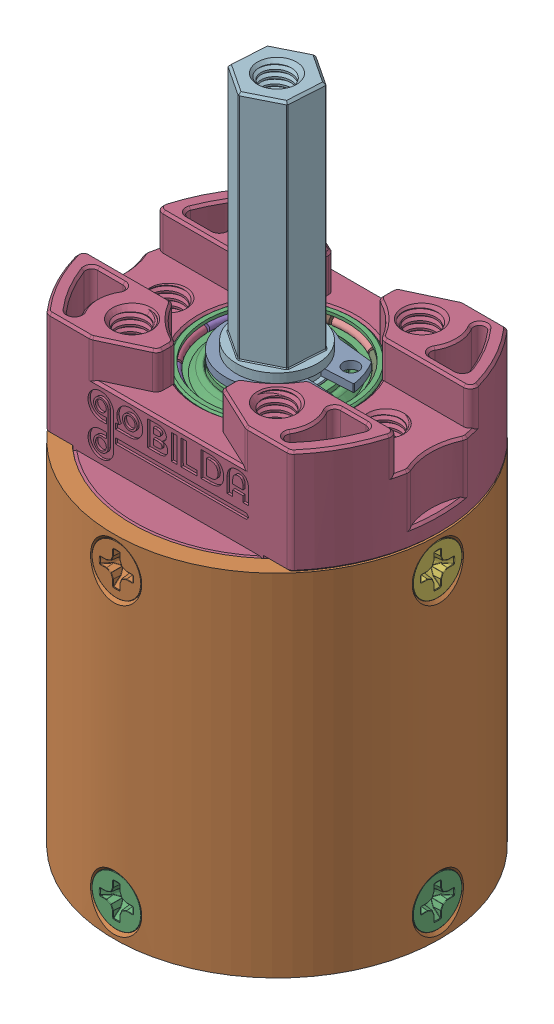
SolidWorks assembly Gearbox, configuration Default. Lengths in mm.
Overall size (36 76.68 35.96).
20 component instances, 8 part files, 0 mates.
Components (placement in the parent):
- Simple-1: Simple [Default] at (-74.1198 0.9931 -10.6145) size (36 73.8 35.96)
  - 5303 Gearbox Base-1: 5303 Gearbox Base [Default] at (-58.7206 21.0354 14.7927) size (31.9 5.6 31.9)
  - 5303 Gearbox Barrel (4 stage, simple)_Gear Blank-1: 5303 Gearbox Barrel (4 stage, simple)_Gear Blank [Default] at (-58.7206 99.2654 14.7927) x (1 0 0) z (0 -1 0) size (35.96 35.96 38.7)
  - 5303 Gearbox Barrel Screw (M3 x 8mm length Flat Head)_92010A118-1: 5303 Gearbox Barrel Screw (M3 x 8mm length Flat Head)_92010A118 [Default] at (-58.7206 24.5354 30.8757) x (0.002439 -0.999997 0) z (0 0 1) size (5.46 5.46 8.05)
  - 5303 Gearbox Face-1: 5303 Gearbox Face [Default] at (-58.7206 54.2354 14.7927) size (36 17.1 31.9)
  - 5303 Gearbox Bearing-1: 5303 Gearbox Bearing [Default] at (-58.7206 62.3354 14.7927) size (17 5 17)
  - 5303 Gearbox Shaft (23.5mm Length, Simple)-1: 5303 Gearbox Shaft (23.5mm Length, Simple) [Default] at (-58.7206 50.8754 14.7927) x (0.894773 0 -0.44652) z (0.44652 0 0.894773) size (8.97 40.6 8.97)
  - 5303 Gearbox Snap Ring-1: 5303 Gearbox Snap Ring [Default] at (-58.7206 67.4104 14.7927) x (0 1 0) z (0 0 1) size (0.85 13.06 10.66)
  - 5303 Gearbox Barrel Screw (M3 x 8mm length Flat Head)_92010A118-2: 5303 Gearbox Barrel Screw (M3 x 8mm length Flat Head)_92010A118 [Default] at (-58.7206 56.2354 30.8757) x (-0.002439 -0.999997 0) z (0 0 1) size (5.46 5.46 8.05)
  - 5303 Gearbox Barrel Screw (M3 x 8mm length Flat Head)_92010A118-3: 5303 Gearbox Barrel Screw (M3 x 8mm length Flat Head)_92010A118 [Default] at (-42.6376 24.5354 14.7927) x (0 -0.999997 -0.002439) z (1 0 0) size (5.46 5.46 8.05)
  - 5303 Gearbox Barrel Screw (M3 x 8mm length Flat Head)_92010A118-4: 5303 Gearbox Barrel Screw (M3 x 8mm length Flat Head)_92010A118 [Default] at (-58.7206 24.5354 -1.2903) x (-0.002439 -0.999997 0) z (0 0 -1) size (5.46 5.46 8.05)
  - 5303 Gearbox Barrel Screw (M3 x 8mm length Flat Head)_92010A118-5: 5303 Gearbox Barrel Screw (M3 x 8mm length Flat Head)_92010A118 [Default] at (-74.8037 24.5354 14.7927) x (0 -0.999997 0.002439) z (-1 0 0) size (5.46 5.46 8.05)
  - 5303 Gearbox Barrel Screw (M3 x 8mm length Flat Head)_92010A118-6: 5303 Gearbox Barrel Screw (M3 x 8mm length Flat Head)_92010A118 [Default] at (-42.6376 56.2354 14.7927) x (0 -0.999997 0.002439) z (1 0 0) size (5.46 5.46 8.05)
  - 5303 Gearbox Barrel Screw (M3 x 8mm length Flat Head)_92010A118-7: 5303 Gearbox Barrel Screw (M3 x 8mm length Flat Head)_92010A118 [Default] at (-58.7206 56.2354 -1.2903) x (0.002439 -0.999997 0) z (0 0 -1) size (5.46 5.46 8.05)
  - 5303 Gearbox Barrel Screw (M3 x 8mm length Flat Head)_92010A118-8: 5303 Gearbox Barrel Screw (M3 x 8mm length Flat Head)_92010A118 [Default] at (-74.8037 56.2354 14.7927) x (0 -0.999997 -0.002439) z (-1 0 0) size (5.46 5.46 8.05)
  - 5303 Gearbox Bearing-2: 5303 Gearbox Bearing [Default] at (-58.7206 54.2354 14.7927) size (17 5 17)
- Gearbox Base Mounting Screw M3 x 5mm length SHCS)_91290A110-1: Gearbox Base Mounting Screw M3 x 5mm length SHCS)_91290A110 [Default] at (-141.6792 19.1485 13.0171) x (0.056382 0 0.998409) z (0 -1 0) size (5.5 5.5 8)
- Gearbox Base Mounting Screw M3 x 5mm length SHCS)_91290A110-2: Gearbox Base Mounting Screw M3 x 5mm length SHCS)_91290A110 [Default] at (-124.0016 19.1485 13.0171) x (0.998409 0 -0.056382) z (0 -1 0) size (5.5 5.5 8)
- Gearbox Base Mounting Screw M3 x 5mm length SHCS)_91290A110-3: Gearbox Base Mounting Screw M3 x 5mm length SHCS)_91290A110 [Default] at (-124.0016 19.1485 -4.6606) x (-0.056382 0 -0.998409) z (0 -1 0) size (5.5 5.5 8)
- Gearbox Base Mounting Screw M3 x 5mm length SHCS)_91290A110-4: Gearbox Base Mounting Screw M3 x 5mm length SHCS)_91290A110 [Default] at (-141.6792 19.1485 -4.6606) x (-0.998409 0 0.056382) z (0 -1 0) size (5.5 5.5 8)
